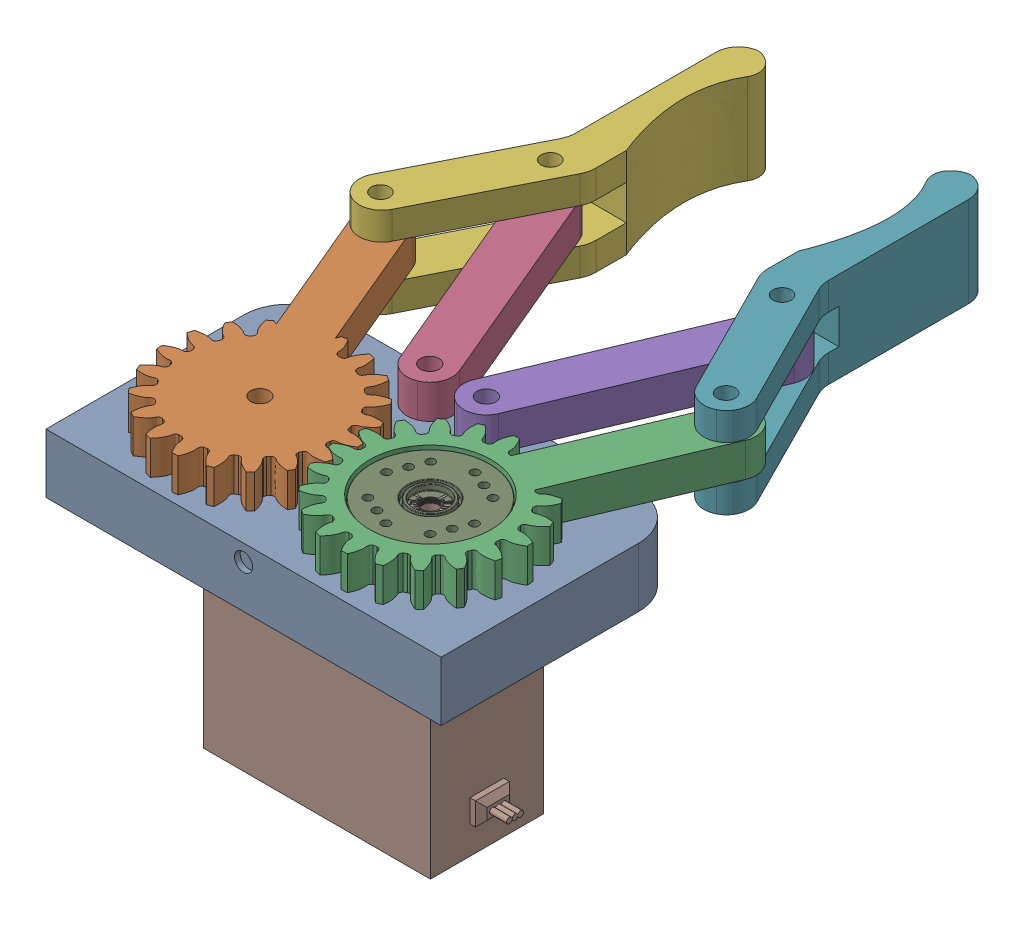
SolidWorks assembly 装配体1, configuration 默认. Lengths in mm.
Overall size (94.4 54.1 114.53).
9 component instances, 7 part files, 22 mates.
Components (placement in the parent):
- 基座2-1: 基座2 [默认] at origin size (70 10.5 43)
- 圆柱齿轮20×1.5-从动2-1: 圆柱齿轮20×1.5-从动2 [默认] at (-15.1 16.5 0) x (-0.971037 0 0.238929) z (0 -1 0) size (32.74 60.86 6)
- 圆柱齿轮20×1.5-主动2-1: 圆柱齿轮20×1.5-主动2 [默认] at (15.1 16.5 0) x (-0.921754 0 -0.387775) z (0 -1 0) size (32.74 61.37 6)
- 拉杆2-1: 拉杆2 [默认] at (-12.7702 10.5 -38.4341) x (0.387891 0 0.921705) z (-0.921705 0 0.387891) size (48 6 8)
- 拉杆2-2: 拉杆2 [默认] at (12.7679 10.5 -38.4351) x (-0.387775 0 0.921754) z (-0.921754 0 -0.387775) size (48 6 8)
- 夹手-1: 夹手 [默认] at (-25.5804 16.6 -46.8725) x (0.451103 0 -0.892472) z (0.892472 0 0.451103) size (58.63 16 20.15)
- 夹手-3: 夹手 [默认] at (25.5672 10.4 -46.8702) x (-0.45034 0 -0.892857) z (-0.892857 0 0.45034) size (58.63 16 20.15)
- MG995舵机模型-1: MG995舵机模型 [默认] at (5 -2.5 0) size (53.2 47.5 20)
- 圆法兰盘1-1: 圆法兰盘1 [默认] at (15.1 13.5 0) x (0.387775 0 -0.921754) z (0.921754 0 0.387775) size (21 5.5 21)
Mates (geometry in assembly coordinates):
- 同心1: concentric anti-aligned: cylinder of 基座2-1 through (15.1 14.5 0) axis (0 -1 0) radius 7; cylinder of 圆柱齿轮20×1.5-主动2-1 through (15.1 13.5 0) axis (0 1 0) radius 10.75
- 重合1: coincident anti-aligned: plane of 基座2-1 through (0 10.5 0) normal (0 1 0); plane of 圆柱齿轮20×1.5-主动2-1 through (15.1 10.5 0) normal (0 -1 0)
- 重合2: coincident anti-aligned: plane of 基座2-1 through (0 10.5 0) normal (0 1 0); plane of 圆柱齿轮20×1.5-从动2-1 through (-15.1 10.5 0) normal (0 -1 0)
- 同心3: concentric aligned: cylinder of 基座2-1 through (-5.0124 -9.5 -20) axis (0 1 0) radius 1.525; cylinder of 拉杆2-1 through (-5.0124 1.5 -20) axis (0 1 0) radius 1.65
- 重合3: coincident anti-aligned: plane of 基座2-1 through (0 10.5 0) normal (0 1 0); plane of 拉杆2-1 through (-12.7702 10.5 -38.4341) normal (0 -1 0)
- 同心4: concentric aligned: cylinder of 基座2-1 through (5.0124 -9.5 -20) axis (0 1 0) radius 1.525; cylinder of 拉杆2-2 through (5.0124 1.5 -20) axis (0 1 0) radius 1.65
- 重合4: coincident aligned: plane of 拉杆2-1 through (-12.7702 16.5 -38.4341) normal (0 1 0); plane of 拉杆2-2 through (12.7679 16.5 -38.4351) normal (0 1 0)
- 平行3: parallel aligned: plane of 圆柱齿轮20×1.5-从动2-1 through (-16.1536 57.4639 -12.8157) normal (0.921705 0 -0.387891); plane of 拉杆2-1 through (-18.3928 16.5 -62.1066) normal (0.921705 0 -0.387891)
- 平行4: parallel anti-aligned: plane of 圆柱齿轮20×1.5-主动2-1 through (30.8018 -28.7586 -47.6388) normal (-0.921754 0 -0.387775); plane of 拉杆2-2 through (25.7615 16.5 -59.0061) normal (0.921754 0 0.387775)
- 同心5: concentric anti-aligned: cylinder of 基座2-1 through (-15.1 -4.5 0) axis (0 1 0) radius 1.5; cylinder of 圆柱齿轮20×1.5-从动2-1 through (-15.1 23.5 0) axis (0 -1 0) radius 1.65
- 同心6: concentric anti-aligned: cylinder of 拉杆2-1 through (-20.528 1.5 -56.8682) axis (0 1 0) radius 1.65; cylinder of 夹手-1 through (-20.528 21.6 -56.8682) axis (0 -1 0) radius 1.6
- 重合9: coincident anti-aligned: plane of 圆柱齿轮20×1.5-从动2-1 through (-15.1 10.5 0) normal (0 -1 0); plane of 夹手-1 through (-25.5804 10.5 -46.8725) normal (0 1 0)
- 齿轮配合1: gear = 30 : 30 mm: circle of 圆柱齿轮20×1.5-从动2-1; circle of 圆柱齿轮20×1.5-主动2-1
- 同心11: concentric aligned: cylinder of 拉杆2-2 through (20.5234 1.5 -56.8702) axis (0 1 0) radius 1.65; cylinder of 夹手-3 through (20.5234 5.4 -56.8702) axis (0 1 0) radius 1.6
- 重合10: coincident anti-aligned: plane of 拉杆2-2 through (12.7679 16.5 -38.4351) normal (0 1 0); plane of 夹手-3 through (25.5672 16.5 -46.8702) normal (0 -1 0)
- 同心12: concentric aligned: cylinder of 圆柱齿轮20×1.5-主动2-1 through (30.611 6.5 -36.8702) axis (0 1 0) radius 1.6; cylinder of 夹手-3 through (30.611 5.4 -36.8702) axis (0 1 0) radius 1.6
- 平行7: parallel anti-aligned: plane of 夹手-1 through (-15.2296 -20.3202 -92.061) normal (1 0 0.000428); plane of 夹手-3 through (15.255 47.3202 -92.0674) normal (-1 0 -0.000428)
- 重合11: coincident anti-aligned: plane of 基座2-1 through (0 0 0) normal (0 -1 0); plane of MG995舵机模型-1 through (5 0 0) normal (0 1 0)
- 同心14: concentric aligned: cylinder of 圆柱齿轮20×1.5-主动2-1 through (15.1 10.5 0) axis (0 1 0) radius 5; cylinder of MG995舵机模型-1 through (15.1 12 0) axis (0 1 0) radius 1.5
- 重合12: coincident anti-aligned: plane of 圆柱齿轮20×1.5-主动2-1 through (15.1 13.5 0) normal (0 1 0); plane of 圆法兰盘1-1 through (15.1 13.5 0) normal (0 -1 0)
- 同心15: concentric aligned: cylinder of 圆柱齿轮20×1.5-主动2-1 through (12.2886 10.5 6.6827) axis (0 1 0) radius 0.75; cylinder of 圆法兰盘1-1 through (12.2886 13 6.6827) axis (0 1 0) radius 0.75
- 同心16: concentric aligned: cylinder of 圆柱齿轮20×1.5-主动2-1 through (8.4173 10.5 -2.8114) axis (0 1 0) radius 0.75; cylinder of 圆法兰盘1-1 through (8.4173 13 -2.8114) axis (0 1 0) radius 0.75
